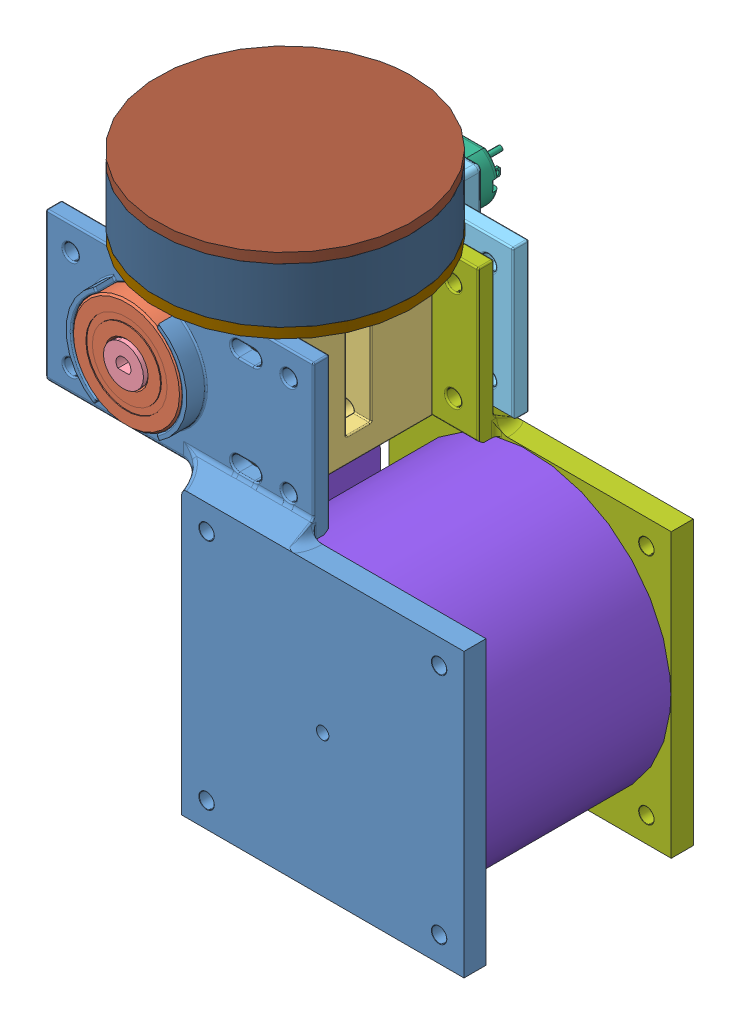
SolidWorks assembly Sprocket Prototype 9 (1), configuration Default. Lengths in mm.
Overall size (95 102 80.29).
13 component instances, 11 part files, 23 mates.
Components (placement in the parent):
- Combined Side Plate Left 9 (1)-1: Combined Side Plate Left 9 (1) [Default] at origin size (88.84 86.77 8.42)
- 5972K222_BALL BEARING 9 (1)-1: 5972K222_BALL BEARING 9 (1) [5972K222] at (20 15 3.5) size (22 22 7)
- Back Plate 9 (1)-1: Back Plate 9 (1) [Default] at (44.6711 0 -29.85) x (0 0 1) z (-1 0 0) size (29.85 30 12.5)
- Custom Axle Sprocket 9 (1)-1: Custom Axle Sprocket 9 (1) [6 tooth BD] at (20 15 -37.45) size (30 45.38 45.05)
- 5972K222_BALL BEARING 9 (1)-2: 5972K222_BALL BEARING 9 (1) [5972K222] at (20 15 -33.35) x (-0.381749 -0.924266 0) z (0 0 1) size (22 22 7)
- Motor Mount 9 (1)-1: Motor Mount 9 (1) [Default] at (12.4 21.5 -57.025) x (-1 0 0) z (0 0 1) size (53.75 30 20.17)
- Pololu Motor 9 (1)-1: Pololu Motor 9 (1) [Default] at (20 15 -47.05) x (0 0 1) z (1 0 0) size (39.27 10 12)
- Combined Side Plate Right 9 (1)-1: Combined Side Plate Right 9 (1) [Default] at (0 0 -9.85) size (88.84 86.77 8.42)
- Fake Tape Measure (1)-1: Fake Tape Measure (1) [Default] at (60.5 -28.3845 -37.375) x (0.999993 0.00369 0) z (0 0 1) size (56.9 86.75 43)
- Tip Mass-1: Tip Mass [Default] at (-7.0852 5.5994 8.8247) x (-0.124999 -0.000461 -0.992157) z (0.99215 0.003661 -0.125) size (51 15 51)
  - Tip Mass Bottom Plate (1)-1: Tip Mass Bottom Plate (1) [Default] at (20.4018 24.2669 38.6628) x (1 0 0) z (0 1 0) size (51 51 4)
  - Tip Mass Side Wall (1)-1: Tip Mass Side Wall (1) [Default] at (20.4018 37.2669 38.6628) x (1 0 0) z (0 -1 0) size (51 51 11)
  - Tip Mass Top Plate (1)-1: Tip Mass Top Plate (1) [Default] at (20.4018 39.2669 38.6628) x (1 0 0) z (0 -1 0) size (51 51 4)
Mates (geometry in assembly coordinates):
- Concentric1: concentric anti-aligned: cylinder of Combined Side Plate Left 9-1 through (20 15 3.175) axis (0 0 -1) radius 11; cylinder of 5972K222_BALL BEARING 9-1 through (20 15 7) axis (0 0 1) radius 4
- Coincident1: coincident aligned: plane of Combined Side Plate Left 9-1 through (0 0 0) normal (0 0 -1); plane of 5972K222_BALL BEARING 9-1 through (20 19.35 0) normal (0 0 -1)
- Coincident2: coincident anti-aligned: plane of Combined Side Plate Left 9-1 through (0 0 0) normal (0 0 -1); plane of Back Plate 9-1 through (32.1711 0 0) normal (0 0 1)
- Coincident3: coincident aligned: plane of Combined Side Plate Left 9-1 through (0 30 3.175) normal (0 1 0); plane of Back Plate 9-1 through (32.1711 30 -29.85) normal (0 1 0)
- Concentric2: concentric anti-aligned: cylinder of 5972K222_BALL BEARING 9-1 through (20 15 7) axis (0 0 1) radius 4; cylinder of Custom Axle Sprocket 9-1 through (20 15 7.6) axis (0 0 -1) radius 4.025
- Coincident4: coincident anti-aligned: plane of 5972K222_BALL BEARING 9-1 through (20 19.35 0) normal (0 0 -1); plane of Custom Axle Sprocket 9-1 through (20 15 0) normal (0 0 1)
- Concentric4: concentric anti-aligned: cylinder of Custom Axle Sprocket 9-1 through (20 15 7.6) axis (0 0 -1) radius 4.025; cylinder of 5972K222_BALL BEARING 9-2 through (20 15 -29.85) axis (0 0 1) radius 4
- Coincident6: coincident anti-aligned: plane of Custom Axle Sprocket 9-1 through (20 15 -29.85) normal (0 0 -1); plane of 5972K222_BALL BEARING 9-2 through (26.3226 12.3886 -29.85) normal (0 0 1)
- Concentric6: concentric anti-aligned: cylinder of Custom Axle Sprocket 9-1 through (20 15 -27.45) axis (0 0 -1) radius 1.5; cylinder of Pololu Motor 9-1 through (20 15 -68.05) axis (0 0 1) radius 0.5
- Parallel2: parallel anti-aligned: plane of Motor Mount 9-1 through (26 9.7 -40.025) normal (0 1 0); plane of Pololu Motor 9-1 through (23.3166 10 -62.05) normal (0 -1 0)
- Coincident14: coincident anti-aligned: plane of Custom Axle Sprocket 9-1 through (20 15 -37.45) normal (0 0 -1); plane of Pololu Motor 9-1 through (20 15 -37.45) normal (0 0 1)
- Concentric7: concentric aligned: cylinder of 5972K222_BALL BEARING 9-2 through (20 15 -29.85) axis (0 0 1) radius 11; cylinder of Combined Side Plate Right 9-1 through (20 15 -33.025) axis (0 0 1) radius 11
- Coincident16: coincident aligned: plane of 5972K222_BALL BEARING 9-2 through (26.3226 12.3886 -29.85) normal (0 0 1); plane of Combined Side Plate Right 9-1 through (0 0 -29.85) normal (0 0 1)
- Coincident17: coincident aligned: plane of Combined Side Plate Left 9-1 through (0 30 3.175) normal (0 1 0); plane of Combined Side Plate Right 9-1 through (0 30 -33.025) normal (0 1 0)
- Coincident18: coincident aligned: plane of Motor Mount 9-1 through (53.75 30 -36.85) normal (0 1 0); plane of Combined Side Plate Right 9-1 through (0 30 -33.025) normal (0 1 0)
- Coincident19: coincident aligned: plane of Motor Mount 9-1 through (0 0 -36.85) normal (-1 0 0); plane of Combined Side Plate Right 9-1 through (0 0 -33.025) normal (-1 0 0)
- Coincident20: coincident anti-aligned: plane of Motor Mount 9-1 through (12.4 21.5 -36.85) normal (0 0 1); plane of Combined Side Plate Right 9-1 through (20 15 -36.85) normal (0 0 -1)
- Concentric12: concentric aligned: cylinder of Combined Side Plate Left 9-1 through (60.5 -28.3845 4.4638) axis (0 0 -1) radius 25.7175; cylinder of Fake Tape Measure-1 through (60.5 -28.3845 5.625) axis (0 0 -1) radius 28.25
- Coincident26: coincident anti-aligned: plane of Combined Side Plate Left 9-1 through (0 0 0) normal (0 0 -1); plane of Fake Tape Measure-1 through (32.0343 30.0109 0) normal (0 0 1)
- Coincident27: coincident anti-aligned: plane of Fake Tape Measure-1 through (60.2842 30.1151 -37.375) normal (-0.00369 0.999993 0); plane of Tip Mass-1/Tip Mass Bottom Plate-1 through (28.6344 29.9983 -16.25) normal (0.00369 -0.999993 0)
- Tangent5: tangent anti-aligned: plane of Fake Tape Measure-1 through (31.6343 30.0094 0) normal (-0.999993 -0.00369 0); cylinder of Tip Mass-1/Tip Mass Bottom Plate-1 through (29.6196 34.002 -8.3127) axis (0.00369 -0.999993 0) radius 2
- Tangent6: tangent anti-aligned: plane of Fake Tape Measure-1 through (31.6343 30.0094 0) normal (-0.999993 -0.00369 0); cylinder of Tip Mass-1/Tip Mass Bottom Plate-1 through (28.6196 33.9983 -16.25) axis (0.00369 -0.999993 0) radius 3
- Distance1: distance = 12.5 mm: cylinder of Tip Mass-1/Tip Mass Bottom Plate-1 through (28.6196 33.9983 -16.25) axis (0.00369 -0.999993 0) radius 3; plane of Fake Tape Measure-1 through (31.6343 30.0094 -31.75) normal (0 0 -1)
